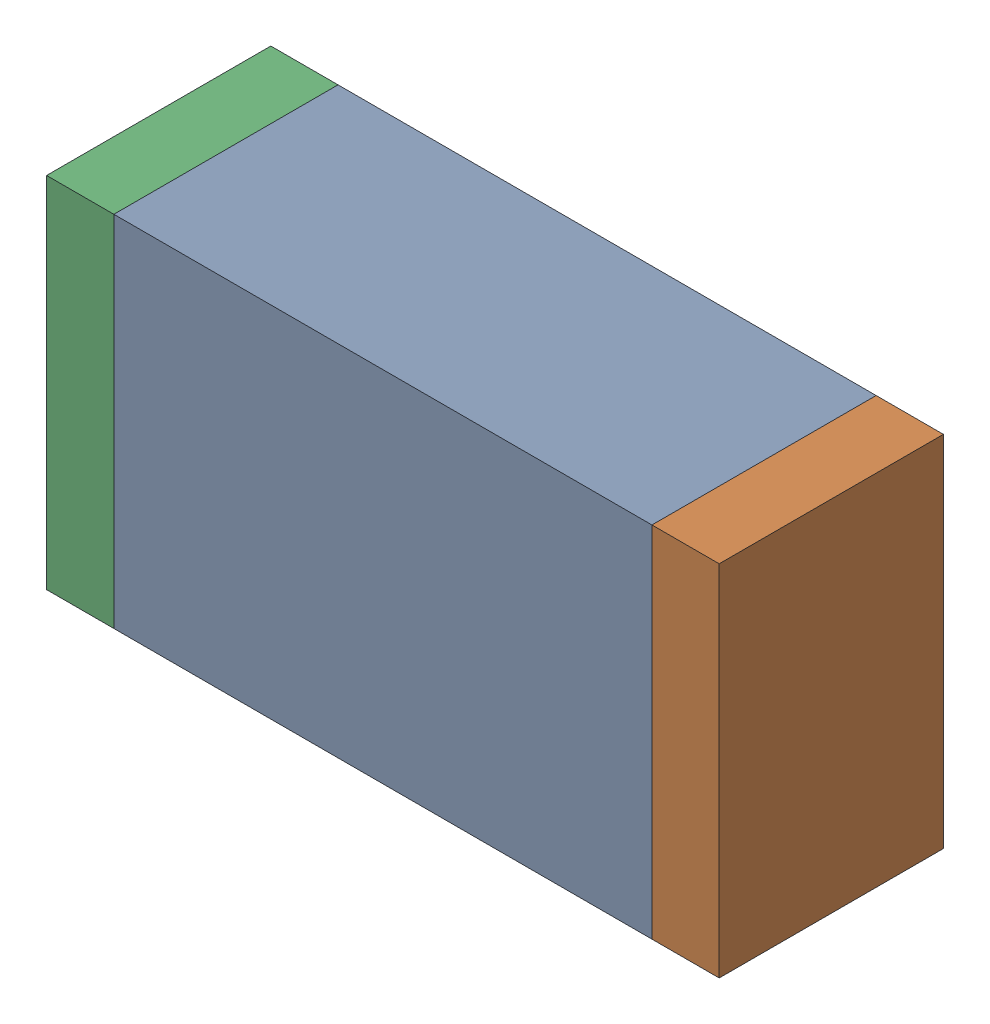
SolidWorks assembly C43, configuration Default. Lengths in mm.
Overall size (1.5 0.8 0.5).
6 component instances, 2 part files, 0 mates.
Components (placement in the parent):
- 836752368-1: 836752368 [Default] at (119.2 36.95 0) size (1.2 0.8 0.5)
  - Extruded-1: Extruded [Default] at origin size (1.2 0.8 0.5)
- 836752496-1: 836752496 [Default] at (119.875 36.95 0) size (0.15 0.8 0.5)
  - Extruded_2-1: Extruded_2 [Default] at origin size (0.15 0.8 0.5)
- 836752496-2: 836752496 [Default] at (118.525 36.95 0) size (0.15 0.8 0.5)
  - Extruded_2-1: Extruded_2 [Default] at origin size (0.15 0.8 0.5)
